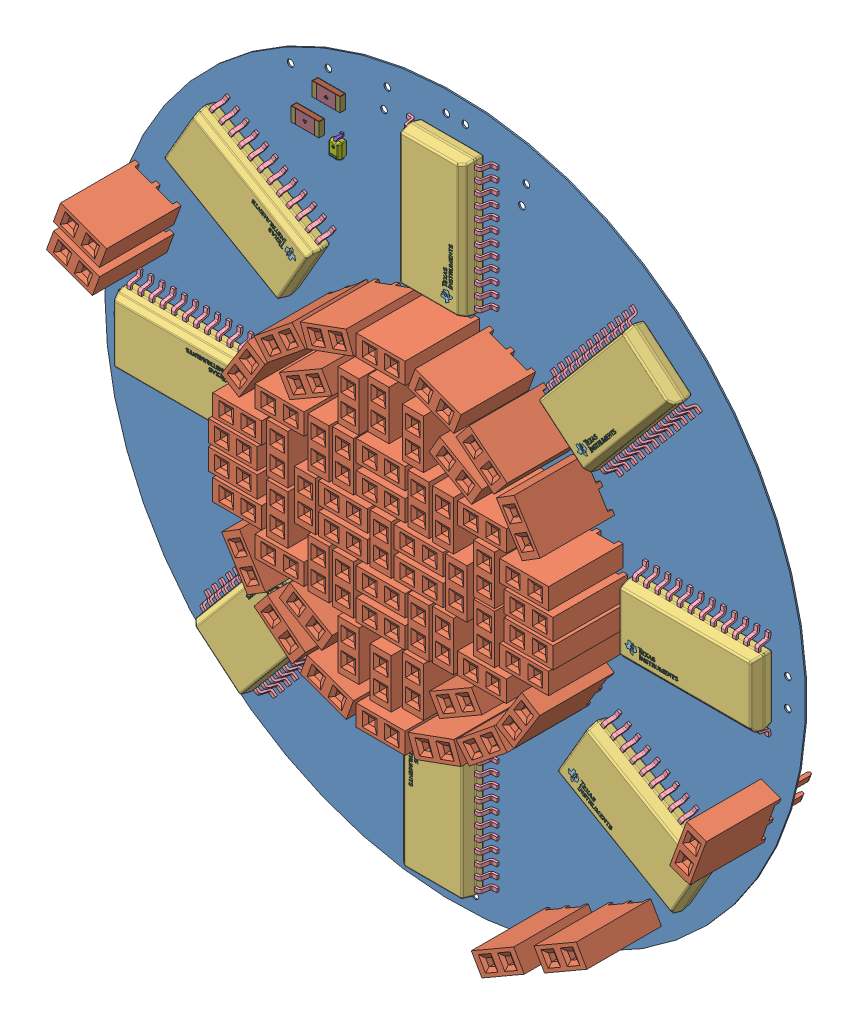
SolidWorks assembly mounting_pcb, configuration Défaut. Lengths in mm.
Overall size (80 80 13.44).
384 component instances, 15 part files, 0 mates.
Components (placement in the parent):
- Board-1: Board [Défaut] at origin size (80 80 0.16)
  - Open CASCADE STEP translator 7.5 1.1.1-1: Open CASCADE STEP translator 7.5 1.1.1 [Défaut] at (0 0 -0.1614) size (80 80 0.16)
- 12-1: 12 [Défaut] at origin size (2.41 5.59 13.44)
  - SSW-102-02-X-S-1: SSW-102-02-X-S [Défaut] at (-11.8109 -2.9211 0) x (1 0 0) z (0 -1 0) size (2.41 13.44 5.59)
- extra3-1: extra3 [Défaut] at origin size (6.05 4.88 13.44)
  - SSW-102-02-X-S-1: SSW-102-02-X-S [Défaut] at (13.3781 -34.6711 0) x (0.5 -0.866025 0) z (-0.866025 -0.5 0) size (2.41 13.44 5.59)
- extra4-1: extra4 [Défaut] at origin size (6.05 4.88 13.44)
  - SSW-102-02-X-S-1: SSW-102-02-X-S [Défaut] at (20.5308 -30.6071 0) x (0.5 -0.866025 0) z (-0.866025 -0.5 0) size (2.41 13.44 5.59)
- extra5-1: extra5 [Défaut] at origin size (4.18 6.08 13.44)
  - SSW-102-02-X-S-1: SSW-102-02-X-S [Défaut] at (35.1053 -13.0305 0) x (-0.939693 0.34202 0) z (0.34202 0.939693 0) size (2.41 13.44 5.59)
- 42-1: 42 [Défaut] at origin size (2.41 5.59 13.44)
  - SSW-102-02-X-S-1: SSW-102-02-X-S [Défaut] at (4.3181 -6.0961 0) x (1 0 0) z (0 -1 0) size (2.41 13.44 5.59)
- extra 1-1: extra 1 [Défaut] at origin size (6.08 4.18 13.44)
  - SSW-102-02-X-S-1: SSW-102-02-X-S [Défaut] at (-35.1287 10.2336 0) x (-0.34202 -0.939693 0) z (-0.939693 0.34202 0) size (2.41 13.44 5.59)
- extra 2-1: extra 2 [Défaut] at origin size (6.08 4.18 13.44)
  - SSW-102-02-X-S-1: SSW-102-02-X-S [Défaut] at (-34.3405 13.3883 0) x (-0.34202 -0.939693 0) z (-0.939693 0.34202 0) size (2.41 13.44 5.59)
- U5-1: U5 [Défaut] at origin size (10.34 15.4 2.65)
  - IC_Texas_Instruments_CD74HC4067M96_eec-1: IC_Texas_Instruments_CD74HC4067M96_eec [Défaut] at (-0.127 28.575 0) x (1 0 0) z (0 0 1) size (10.34 15.4 2.65)
    - BODY-SO-1: BODY-SO [Défaut] at (0 0 1.0825) x (0 1 0) z (1 0 0) size (15.4 2.45 7.5)
    - LEAD-SO-1: LEAD-SO [Défaut] at (4.315 6.985 0.25) x (0 1 0) z (1 0 0) size (0.41 1.43 1.42)
    - LEAD-SO-2: LEAD-SO [Défaut] at (4.315 5.715 0.25) x (0 1 0) z (1 0 0) size (0.41 1.43 1.42)
    - LEAD-SO-3: LEAD-SO [Défaut] at (4.315 4.445 0.25) x (0 1 0) z (1 0 0) size (0.41 1.43 1.42)
    - LEAD-SO-4: LEAD-SO [Défaut] at (4.315 3.175 0.25) x (0 1 0) z (1 0 0) size (0.41 1.43 1.42)
    - LEAD-SO-5: LEAD-SO [Défaut] at (4.315 1.905 0.25) x (0 1 0) z (1 0 0) size (0.41 1.43 1.42)
    - LEAD-SO-6: LEAD-SO [Défaut] at (4.315 0.635 0.25) x (0 1 0) z (1 0 0) size (0.41 1.43 1.42)
    - LEAD-SO-7: LEAD-SO [Défaut] at (4.315 -0.635 0.25) x (0 1 0) z (1 0 0) size (0.41 1.43 1.42)
    - LEAD-SO-8: LEAD-SO [Défaut] at (4.315 -1.905 0.25) x (0 1 0) z (1 0 0) size (0.41 1.43 1.42)
    - LEAD-SO-9: LEAD-SO [Défaut] at (4.315 -3.175 0.25) x (0 1 0) z (1 0 0) size (0.41 1.43 1.42)
    - LEAD-SO-10: LEAD-SO [Défaut] at (4.315 -4.445 0.25) x (0 1 0) z (1 0 0) size (0.41 1.43 1.42)
    - LEAD-SO-11: LEAD-SO [Défaut] at (4.315 -5.715 0.25) x (0 1 0) z (1 0 0) size (0.41 1.43 1.42)
    - LEAD-SO-12: LEAD-SO [Défaut] at (4.315 -6.985 0.25) x (0 1 0) z (1 0 0) size (0.41 1.43 1.42)
    - LEAD-SO-13: LEAD-SO [Défaut] at (-4.315 6.985 0.25) x (0 -1 0) z (-1 0 0) size (0.41 1.43 1.42)
    - LEAD-SO-14: LEAD-SO [Défaut] at (-4.315 5.715 0.25) x (0 -1 0) z (-1 0 0) size (0.41 1.43 1.42)
    - LEAD-SO-15: LEAD-SO [Défaut] at (-4.315 4.445 0.25) x (0 -1 0) z (-1 0 0) size (0.41 1.43 1.42)
    - LEAD-SO-16: LEAD-SO [Défaut] at (-4.315 3.175 0.25) x (0 -1 0) z (-1 0 0) size (0.41 1.43 1.42)
    - LEAD-SO-17: LEAD-SO [Défaut] at (-4.315 1.905 0.25) x (0 -1 0) z (-1 0 0) size (0.41 1.43 1.42)
    - LEAD-SO-18: LEAD-SO [Défaut] at (-4.315 0.635 0.25) x (0 -1 0) z (-1 0 0) size (0.41 1.43 1.42)
    - LEAD-SO-19: LEAD-SO [Défaut] at (-4.315 -0.635 0.25) x (0 -1 0) z (-1 0 0) size (0.41 1.43 1.42)
    - LEAD-SO-20: LEAD-SO [Défaut] at (-4.315 -1.905 0.25) x (0 -1 0) z (-1 0 0) size (0.41 1.43 1.42)
    - LEAD-SO-21: LEAD-SO [Défaut] at (-4.315 -3.175 0.25) x (0 -1 0) z (-1 0 0) size (0.41 1.43 1.42)
    - LEAD-SO-22: LEAD-SO [Défaut] at (-4.315 -4.445 0.25) x (0 -1 0) z (-1 0 0) size (0.41 1.43 1.42)
    - LEAD-SO-23: LEAD-SO [Défaut] at (-4.315 -5.715 0.25) x (0 -1 0) z (-1 0 0) size (0.41 1.43 1.42)
    - LEAD-SO-24: LEAD-SO [Défaut] at (-4.315 -6.985 0.25) x (0 -1 0) z (-1 0 0) size (0.41 1.43 1.42)
    - Texas Logo Yury-1: Texas Logo Yury [Défaut] at (2.174 -7.1221 2.551) x (0 1 0) z (0 0 1) size (1.32 1.29 0.11)
    - Texas Logo Yury - Copy-1: Texas Logo Yury - Copy [Défaut] at (2.0641 -7.1534 2.551) x (0 1 0) z (0 0 1) size (4.61 1.2 0.1)
- Zener1-1: Zener1 [Défaut] at origin size (1.25 2.5 1.12)
  - Diode_ON_Semiconductor_NSR02100HT1G_eec-1: Diode_ON_Semiconductor_NSR02100HT1G_eec [Défaut] at (-12.827 28.829 0) x (0 1 0) z (0 0 1) size (2.5 1.25 1.12)
    - 1-1: 1 [Défaut] at (0 0 0.05) size (1.7 1.25 1.08)
    - 2-1: 2 [Défaut] x (1 0 0) z (0 -1 0) size (2.5 0.9 0.32)
    - ON Semiconductor-1: ON Semiconductor [Défaut] at (0.2865 -0.4575 1.0977) size (0.43 0.38 0.01)
    - bar-1: bar [Défaut] at (0 0 1.1) size (0.22 0.81 0)
- 6-1: 6 [Défaut] at origin size (3.2 1.6 0.65)
  - Res_Vishay_MCA12060D1541BP100_eec-1: Res_Vishay_MCA12060D1541BP100_eec [Défaut] at (-16.5038 29.591 0) x (1 0 0) z (0 0 1) size (3.2 1.6 0.65)
    - body-1: body [Défaut] at (0 0 0.6) x (1 0 0) z (0 0 -1) size (3.1 1.6 0.55)
    - pad-1: pad [Défaut] at (-1.4133 -0.8 0.65) x (1 0 0) z (0 1 0) size (0.5 0.65 1.6)
    - pad-2: pad [Défaut] at (1.4133 0.8 0.65) x (-1 0 0) z (0 -1 0) size (0.5 0.65 1.6)
    - top-1: top [Défaut] at (0 0 0.65) x (1 0 0) z (0 0 -1) size (2.2 1.6 0.05)
    - Vishay-1: Vishay [Défaut] at (0.0405 -0.7888 0.65) size (0.45 0.38 0.01)
    - bottom-1: bottom [Défaut] at (0 0 0.05) x (1 0 0) z (0 0 -1) size (2.2 1.6 0.05)
- res1-1: res1 [Défaut] at origin size (3.2 1.6 0.65)
  - Res_Vishay_MCA12060D1541BP100_eec-1: Res_Vishay_MCA12060D1541BP100_eec [Défaut] at (-14.097 33.274 0) x (-1 0 0) z (0 0 1) size (3.2 1.6 0.65)
    - body-1: body [Défaut] at (0 0 0.6) x (1 0 0) z (0 0 -1) size (3.1 1.6 0.55)
    - pad-1: pad [Défaut] at (-1.4133 -0.8 0.65) x (1 0 0) z (0 1 0) size (0.5 0.65 1.6)
    - pad-2: pad [Défaut] at (1.4133 0.8 0.65) x (-1 0 0) z (0 -1 0) size (0.5 0.65 1.6)
    - top-1: top [Défaut] at (0 0 0.65) x (1 0 0) z (0 0 -1) size (2.2 1.6 0.05)
    - Vishay-1: Vishay [Défaut] at (0.0405 -0.7888 0.65) size (0.45 0.38 0.01)
    - bottom-1: bottom [Défaut] at (0 0 0.05) x (1 0 0) z (0 0 -1) size (2.2 1.6 0.05)
- 60-1: 60 [Défaut] at origin size (5.59 2.41 13.44)
  - SSW-102-02-X-S-1: SSW-102-02-X-S [Défaut] at (16.8911 1.3971 0) x (0 1 0) z (1 0 0) size (2.41 13.44 5.59)
- 58-1: 58 [Défaut] at origin size (5.59 2.41 13.44)
  - SSW-102-02-X-S-1: SSW-102-02-X-S [Défaut] at (16.3831 4.1911 0) x (0 1 0) z (1 0 0) size (2.41 13.44 5.59)
- 56-1: 56 [Défaut] at origin size (5.01 6.02 13.44)
  - SSW-102-02-X-S-1: SSW-102-02-X-S [Défaut] at (15.7101 9.459 0) x (0.848048 0.529919 0) z (0.529919 -0.848048 0) size (2.41 13.44 5.59)
- 49-1: 49 [Défaut] at origin size (5.86 5.39 13.44)
  - SSW-102-02-X-S-1: SSW-102-02-X-S [Défaut] at (11.5281 14.0968 0) x (0.62932 0.777146 0) z (0.777146 -0.62932 0) size (2.41 13.44 5.59)
- 41-1: 41 [Défaut] at origin size (6.08 4.18 13.44)
  - SSW-102-02-X-S-1: SSW-102-02-X-S [Défaut] at (6.1465 17.2187 0) x (0.34202 0.939693 0) z (0.939693 -0.34202 0) size (2.41 13.44 5.59)
- 54-1: 54 [Défaut] at origin size (2.41 5.59 13.44)
  - SSW-102-02-X-S-1: SSW-102-02-X-S [Défaut] at (11.8109 2.9211 0) x (-1 0 0) z (0 1 0) size (2.41 13.44 5.59)
- 52-1: 52 [Défaut] at origin size (5.59 2.41 13.44)
  - SSW-102-02-X-S-1: SSW-102-02-X-S [Défaut] at (11.5571 7.4931 0) x (0 1 0) z (1 0 0) size (2.41 13.44 5.59)
- 45-1: 45 [Défaut] at origin size (6.05 4.88 13.44)
  - SSW-102-02-X-S-1: SSW-102-02-X-S [Défaut] at (8.5523 11.557 0) x (0.5 0.866025 0) z (0.866025 -0.5 0) size (2.41 13.44 5.59)
- 39-1: 39 [Défaut] at origin size (2.41 5.59 13.44)
  - SSW-102-02-X-S-1: SSW-102-02-X-S [Défaut] at (3.6829 12.3191 0) x (-1 0 0) z (0 1 0) size (2.41 13.44 5.59)
- 33-1: 33 [Défaut] at origin size (2.41 5.59 13.44)
  - SSW-102-02-X-S-1: SSW-102-02-X-S [Défaut] at (-0.2541 13.2081 0) x (-1 0 0) z (0 1 0) size (2.41 13.44 5.59)
- 47-1: 47 [Défaut] at origin size (2.41 5.59 13.44)
  - SSW-102-02-X-S-1: SSW-102-02-X-S [Défaut] at (7.1119 5.9691 0) x (-1 0 0) z (0 1 0) size (2.41 13.44 5.59)
- 43-1: 43 [Défaut] at origin size (2.41 5.59 13.44)
  - SSW-102-02-X-S-1: SSW-102-02-X-S [Défaut] at (4.3179 6.0961 0) x (-1 0 0) z (0 1 0) size (2.41 13.44 5.59)
- 31-1: 31 [Défaut] at origin size (5.59 2.41 13.44)
  - SSW-102-02-X-S-1: SSW-102-02-X-S [Défaut] at (0.0001 7.8741 0) x (0 1 0) z (1 0 0) size (2.41 13.44 5.59)
- 37-1: 37 [Défaut] at origin size (5.59 2.41 13.44)
  - SSW-102-02-X-S-1: SSW-102-02-X-S [Défaut] at (4.3181 1.5241 0) x (0 1 0) z (1 0 0) size (2.41 13.44 5.59)
- 30-1: 30 [Défaut] at origin size (5.59 2.41 13.44)
  - SSW-102-02-X-S-1: SSW-102-02-X-S [Défaut] at (0.0001 4.6991 0) x (0 1 0) z (1 0 0) size (2.41 13.44 5.59)
- 35-1: 35 [Défaut] at origin size (2.41 5.59 13.44)
  - SSW-102-02-X-S-1: SSW-102-02-X-S [Défaut] at (-0.0001 0.0001 0) x (-1 0 0) z (0 1 0) size (2.41 13.44 5.59)
- 36-1: 36 [Défaut] at origin size (5.59 2.41 13.44)
  - SSW-102-02-X-S-1: SSW-102-02-X-S [Défaut] at (4.3181 -1.5239 0) x (0 1 0) z (1 0 0) size (2.41 13.44 5.59)
- 29-1: 29 [Défaut] at origin size (5.59 2.41 13.44)
  - SSW-102-02-X-S-1: SSW-102-02-X-S [Défaut] at (0.0001 -4.6989 0) x (0 1 0) z (1 0 0) size (2.41 13.44 5.59)
- 21-1: 21 [Défaut] at origin size (5.59 2.41 13.44)
  - SSW-102-02-X-S-1: SSW-102-02-X-S [Défaut] at (-4.3181 -1.5241 0) x (0 -1 0) z (-1 0 0) size (2.41 13.44 5.59)
- 22-1: 22 [Défaut] at origin size (5.59 2.41 13.44)
  - SSW-102-02-X-S-1: SSW-102-02-X-S [Défaut] at (-4.3181 1.5239 0) x (0 -1 0) z (-1 0 0) size (2.41 13.44 5.59)
- 48-1: 48 [Défaut] at origin size (2.41 5.59 13.44)
  - SSW-102-02-X-S-1: SSW-102-02-X-S [Défaut] at (8.6359 0.0001 0) x (-1 0 0) z (0 1 0) size (2.41 13.44 5.59)
- 46-1: 46 [Défaut] at origin size (2.41 5.59 13.44)
  - SSW-102-02-X-S-1: SSW-102-02-X-S [Défaut] at (7.1121 -5.9691 0) x (1 0 0) z (0 -1 0) size (2.41 13.44 5.59)
- 16-1: 16 [Défaut] at origin size (2.41 5.59 13.44)
  - SSW-102-02-X-S-1: SSW-102-02-X-S [Défaut] at (-8.6359 -0.0001 0) x (1 0 0) z (0 -1 0) size (2.41 13.44 5.59)
- 28-1: 28 [Défaut] at origin size (5.59 2.41 13.44)
  - SSW-102-02-X-S-1: SSW-102-02-X-S [Défaut] at (0.0001 -7.8739 0) x (0 1 0) z (1 0 0) size (2.41 13.44 5.59)
- 23-1: 23 [Défaut] at origin size (2.41 5.59 13.44)
  - SSW-102-02-X-S-1: SSW-102-02-X-S [Défaut] at (-4.3179 -6.0961 0) x (1 0 0) z (0 -1 0) size (2.41 13.44 5.59)
- 19-1: 19 [Défaut] at origin size (2.41 5.59 13.44)
  - SSW-102-02-X-S-1: SSW-102-02-X-S [Défaut] at (-7.1119 -5.9691 0) x (1 0 0) z (0 -1 0) size (2.41 13.44 5.59)
- 20-1: 20 [Défaut] at origin size (2.41 5.59 13.44)
  - SSW-102-02-X-S-1: SSW-102-02-X-S [Défaut] at (-7.1121 5.9691 0) x (-1 0 0) z (0 1 0) size (2.41 13.44 5.59)
- 24-1: 24 [Défaut] at origin size (2.41 5.59 13.44)
  - SSW-102-02-X-S-1: SSW-102-02-X-S [Défaut] at (-4.3181 6.0961 0) x (-1 0 0) z (0 1 0) size (2.41 13.44 5.59)
- 53-1: 53 [Défaut] at origin size (2.41 5.59 13.44)
  - SSW-102-02-X-S-1: SSW-102-02-X-S [Défaut] at (11.8111 -2.9211 0) x (1 0 0) z (0 -1 0) size (2.41 13.44 5.59)
- 51-1: 51 [Défaut] at origin size (5.59 2.41 13.44)
  - SSW-102-02-X-S-1: SSW-102-02-X-S [Défaut] at (11.5571 -7.3659 0) x (0 1 0) z (1 0 0) size (2.41 13.44 5.59)
- 44-1: 44 [Défaut] at origin size (6.05 4.88 13.44)
  - SSW-102-02-X-S-1: SSW-102-02-X-S [Défaut] at (8.5519 -11.4299 0) x (-0.5 0.866025 0) z (0.866025 0.5 0) size (2.41 13.44 5.59)
- 38-1: 38 [Défaut] at origin size (2.41 5.59 13.44)
  - SSW-102-02-X-S-1: SSW-102-02-X-S [Défaut] at (3.6831 -12.1921 0) x (1 0 0) z (0 -1 0) size (2.41 13.44 5.59)
- 34-1: 34 [Défaut] at origin size (2.41 5.59 13.44)
  - SSW-102-02-X-S-1: SSW-102-02-X-S [Défaut] at (0.0001 -13.2081 0) x (1 0 0) z (0 -1 0) size (2.41 13.44 5.59)
- 25-1: 25 [Défaut] at origin size (2.41 5.59 13.44)
  - SSW-102-02-X-S-1: SSW-102-02-X-S [Défaut] at (-3.6829 -12.3191 0) x (1 0 0) z (0 -1 0) size (2.41 13.44 5.59)
- 14-1: 14 [Défaut] at origin size (6.05 4.88 13.44)
  - SSW-102-02-X-S-1: SSW-102-02-X-S [Défaut] at (-8.5523 -11.43 0) x (-0.5 -0.866025 0) z (-0.866025 0.5 0) size (2.41 13.44 5.59)
- 10-1: 10 [Défaut] at origin size (5.59 2.41 13.44)
  - SSW-102-02-X-S-1: SSW-102-02-X-S [Défaut] at (-11.5571 -7.3661 0) x (0 -1 0) z (-1 0 0) size (2.41 13.44 5.59)
- 13-1: 13 [Défaut] at origin size (2.41 5.59 13.44)
  - SSW-102-02-X-S-1: SSW-102-02-X-S [Défaut] at (-11.8111 3.0481 0) x (-1 0 0) z (0 1 0) size (2.41 13.44 5.59)
- 11-1: 11 [Défaut] at origin size (5.59 2.41 13.44)
  - SSW-102-02-X-S-1: SSW-102-02-X-S [Défaut] at (-11.5571 7.4929 0) x (0 -1 0) z (-1 0 0) size (2.41 13.44 5.59)
- 15-1: 15 [Défaut] at origin size (6.05 4.88 13.44)
  - SSW-102-02-X-S-1: SSW-102-02-X-S [Défaut] at (-8.5519 11.5569 0) x (0.5 -0.866025 0) z (-0.866025 -0.5 0) size (2.41 13.44 5.59)
- 26-1: 26 [Défaut] at origin size (2.41 5.59 13.44)
  - SSW-102-02-X-S-1: SSW-102-02-X-S [Défaut] at (-3.6831 12.3191 0) x (-1 0 0) z (0 1 0) size (2.41 13.44 5.59)
- 32-1: 32 [Défaut] at origin size (5.59 2.41 13.44)
  - SSW-102-02-X-S-1: SSW-102-02-X-S [Défaut] at (0.0001 18.2881 0) x (0 1 0) z (1 0 0) size (2.41 13.44 5.59)
- 59-1: 59 [Défaut] at origin size (5.59 2.41 13.44)
  - SSW-102-02-X-S-1: SSW-102-02-X-S [Défaut] at (16.8911 -1.3969 0) x (0 1 0) z (1 0 0) size (2.41 13.44 5.59)
- 57-1: 57 [Défaut] at origin size (5.59 2.41 13.44)
  - SSW-102-02-X-S-1: SSW-102-02-X-S [Défaut] at (16.3831 -4.1909 0) x (0 1 0) z (1 0 0) size (2.41 13.44 5.59)
- 55-1: 55 [Défaut] at origin size (5.01 6.02 13.44)
  - SSW-102-02-X-S-1: SSW-102-02-X-S [Défaut] at (15.659 -9.5909 0) x (-0.848048 0.529919 0) z (0.529919 0.848048 0) size (2.41 13.44 5.59)
- 50-1: 50 [Défaut] at origin size (5.86 5.39 13.44)
  - SSW-102-02-X-S-1: SSW-102-02-X-S [Défaut] at (11.528 -14.1866 0) x (-0.62932 0.777146 0) z (0.777146 0.62932 0) size (2.41 13.44 5.59)
- 40-1: 40 [Défaut] at origin size (6.08 4.18 13.44)
  - SSW-102-02-X-S-1: SSW-102-02-X-S [Défaut] at (6.1465 -17.2185 0) x (-0.34202 0.939693 0) z (0.939693 0.34202 0) size (2.41 13.44 5.59)
- 27-1: 27 [Défaut] at origin size (5.59 2.41 13.44)
  - SSW-102-02-X-S-1: SSW-102-02-X-S [Défaut] at (-0.0001 -18.2881 0) x (0 -1 0) z (-1 0 0) size (2.41 13.44 5.59)
- 17-1: 17 [Défaut] at origin size (6.08 4.18 13.44)
  - SSW-102-02-X-S-1: SSW-102-02-X-S [Défaut] at (-6.1465 -17.2187 0) x (-0.34202 -0.939693 0) z (-0.939693 0.34202 0) size (2.41 13.44 5.59)
- 8-1: 8 [Défaut] at origin size (5.86 5.39 13.44)
  - SSW-102-02-X-S-1: SSW-102-02-X-S [Défaut] at (-11.5281 -14.1868 0) x (-0.62932 -0.777146 0) z (-0.777146 0.62932 0) size (2.41 13.44 5.59)
- 7-1: 7 [Défaut] at origin size (5.01 6.02 13.44)
  - SSW-102-02-X-S-1: SSW-102-02-X-S [Défaut] at (-15.6591 -9.591 0) x (-0.848048 -0.529919 0) z (-0.529919 0.848048 0) size (2.41 13.44 5.59)
- 3-1: 3 [Défaut] at origin size (5.59 2.41 13.44)
  - SSW-102-02-X-S-1: SSW-102-02-X-S [Défaut] at (-16.3831 -4.1911 0) x (0 -1 0) z (-1 0 0) size (2.41 13.44 5.59)
- 1-1: 1 [Défaut] at origin size (5.59 2.41 13.44)
  - SSW-102-02-X-S-1: SSW-102-02-X-S [Défaut] at (-16.8911 -1.3971 0) x (0 -1 0) z (-1 0 0) size (2.41 13.44 5.59)
- 2-1: 2 [Défaut] at origin size (5.59 2.41 13.44)
  - SSW-102-02-X-S-1: SSW-102-02-X-S [Défaut] at (-16.8911 1.3969 0) x (0 -1 0) z (-1 0 0) size (2.41 13.44 5.59)
- 4-1: 4 [Défaut] at origin size (5.59 2.41 13.44)
  - SSW-102-02-X-S-1: SSW-102-02-X-S [Défaut] at (-16.3831 4.1909 0) x (0 -1 0) z (-1 0 0) size (2.41 13.44 5.59)
- 5-1: 5 [Défaut] at origin size (5.01 6.02 13.44)
  - SSW-102-02-X-S-1: SSW-102-02-X-S [Défaut] at (-15.71 9.4589 0) x (0.848048 -0.529919 0) z (-0.529919 -0.848048 0) size (2.41 13.44 5.59)
- 9-1: 9 [Défaut] at origin size (5.86 5.39 13.44)
  - SSW-102-02-X-S-1: SSW-102-02-X-S [Défaut] at (-11.528 14.1866 0) x (0.62932 -0.777146 0) z (-0.777146 -0.62932 0) size (2.41 13.44 5.59)
- 18-1: 18 [Défaut] at origin size (6.08 4.18 13.44)
  - SSW-102-02-X-S-1: SSW-102-02-X-S [Défaut] at (-6.1465 17.2185 0) x (0.34202 -0.939693 0) z (-0.939693 -0.34202 0) size (2.41 13.44 5.59)
- U8-1: U8 [Défaut] at origin size (15.4 10.34 2.65)
  - IC_Texas_Instruments_CD74HC4067M96_eec-1: IC_Texas_Instruments_CD74HC4067M96_eec [Défaut] at (28.875 0 0) x (0 -1 0) z (0 0 1) size (10.34 15.4 2.65)
    - BODY-SO-1: BODY-SO [Défaut] at (0 0 1.0825) x (0 1 0) z (1 0 0) size (15.4 2.45 7.5)
    - LEAD-SO-1: LEAD-SO [Défaut] at (4.315 6.985 0.25) x (0 1 0) z (1 0 0) size (0.41 1.43 1.42)
    - LEAD-SO-2: LEAD-SO [Défaut] at (4.315 5.715 0.25) x (0 1 0) z (1 0 0) size (0.41 1.43 1.42)
    - LEAD-SO-3: LEAD-SO [Défaut] at (4.315 4.445 0.25) x (0 1 0) z (1 0 0) size (0.41 1.43 1.42)
    - LEAD-SO-4: LEAD-SO [Défaut] at (4.315 3.175 0.25) x (0 1 0) z (1 0 0) size (0.41 1.43 1.42)
    - LEAD-SO-5: LEAD-SO [Défaut] at (4.315 1.905 0.25) x (0 1 0) z (1 0 0) size (0.41 1.43 1.42)
    - LEAD-SO-6: LEAD-SO [Défaut] at (4.315 0.635 0.25) x (0 1 0) z (1 0 0) size (0.41 1.43 1.42)
    - LEAD-SO-7: LEAD-SO [Défaut] at (4.315 -0.635 0.25) x (0 1 0) z (1 0 0) size (0.41 1.43 1.42)
    - LEAD-SO-8: LEAD-SO [Défaut] at (4.315 -1.905 0.25) x (0 1 0) z (1 0 0) size (0.41 1.43 1.42)
    - LEAD-SO-9: LEAD-SO [Défaut] at (4.315 -3.175 0.25) x (0 1 0) z (1 0 0) size (0.41 1.43 1.42)
    - LEAD-SO-10: LEAD-SO [Défaut] at (4.315 -4.445 0.25) x (0 1 0) z (1 0 0) size (0.41 1.43 1.42)
    - LEAD-SO-11: LEAD-SO [Défaut] at (4.315 -5.715 0.25) x (0 1 0) z (1 0 0) size (0.41 1.43 1.42)
    - LEAD-SO-12: LEAD-SO [Défaut] at (4.315 -6.985 0.25) x (0 1 0) z (1 0 0) size (0.41 1.43 1.42)
    - LEAD-SO-13: LEAD-SO [Défaut] at (-4.315 6.985 0.25) x (0 -1 0) z (-1 0 0) size (0.41 1.43 1.42)
    - LEAD-SO-14: LEAD-SO [Défaut] at (-4.315 5.715 0.25) x (0 -1 0) z (-1 0 0) size (0.41 1.43 1.42)
    - LEAD-SO-15: LEAD-SO [Défaut] at (-4.315 4.445 0.25) x (0 -1 0) z (-1 0 0) size (0.41 1.43 1.42)
    - LEAD-SO-16: LEAD-SO [Défaut] at (-4.315 3.175 0.25) x (0 -1 0) z (-1 0 0) size (0.41 1.43 1.42)
    - LEAD-SO-17: LEAD-SO [Défaut] at (-4.315 1.905 0.25) x (0 -1 0) z (-1 0 0) size (0.41 1.43 1.42)
    - LEAD-SO-18: LEAD-SO [Défaut] at (-4.315 0.635 0.25) x (0 -1 0) z (-1 0 0) size (0.41 1.43 1.42)
    - LEAD-SO-19: LEAD-SO [Défaut] at (-4.315 -0.635 0.25) x (0 -1 0) z (-1 0 0) size (0.41 1.43 1.42)
    - LEAD-SO-20: LEAD-SO [Défaut] at (-4.315 -1.905 0.25) x (0 -1 0) z (-1 0 0) size (0.41 1.43 1.42)
    - LEAD-SO-21: LEAD-SO [Défaut] at (-4.315 -3.175 0.25) x (0 -1 0) z (-1 0 0) size (0.41 1.43 1.42)
    - LEAD-SO-22: LEAD-SO [Défaut] at (-4.315 -4.445 0.25) x (0 -1 0) z (-1 0 0) size (0.41 1.43 1.42)
    - LEAD-SO-23: LEAD-SO [Défaut] at (-4.315 -5.715 0.25) x (0 -1 0) z (-1 0 0) size (0.41 1.43 1.42)
    - LEAD-SO-24: LEAD-SO [Défaut] at (-4.315 -6.985 0.25) x (0 -1 0) z (-1 0 0) size (0.41 1.43 1.42)
    - Texas Logo Yury-1: Texas Logo Yury [Défaut] at (2.174 -7.1221 2.551) x (0 1 0) z (0 0 1) size (1.32 1.29 0.11)
    - Texas Logo Yury - Copy-1: Texas Logo Yury - Copy [Défaut] at (2.0641 -7.1534 2.551) x (0 1 0) z (0 0 1) size (4.61 1.2 0.1)
- U4-1: U4 [Défaut] at origin size (10.34 15.4 2.65)
  - IC_Texas_Instruments_CD74HC4067M96_eec-1: IC_Texas_Instruments_CD74HC4067M96_eec [Défaut] at (-0.127 -28.875 0) x (-1 0 0) z (0 0 1) size (10.34 15.4 2.65)
    - BODY-SO-1: BODY-SO [Défaut] at (0 0 1.0825) x (0 1 0) z (1 0 0) size (15.4 2.45 7.5)
    - LEAD-SO-1: LEAD-SO [Défaut] at (4.315 6.985 0.25) x (0 1 0) z (1 0 0) size (0.41 1.43 1.42)
    - LEAD-SO-2: LEAD-SO [Défaut] at (4.315 5.715 0.25) x (0 1 0) z (1 0 0) size (0.41 1.43 1.42)
    - LEAD-SO-3: LEAD-SO [Défaut] at (4.315 4.445 0.25) x (0 1 0) z (1 0 0) size (0.41 1.43 1.42)
    - LEAD-SO-4: LEAD-SO [Défaut] at (4.315 3.175 0.25) x (0 1 0) z (1 0 0) size (0.41 1.43 1.42)
    - LEAD-SO-5: LEAD-SO [Défaut] at (4.315 1.905 0.25) x (0 1 0) z (1 0 0) size (0.41 1.43 1.42)
    - LEAD-SO-6: LEAD-SO [Défaut] at (4.315 0.635 0.25) x (0 1 0) z (1 0 0) size (0.41 1.43 1.42)
    - LEAD-SO-7: LEAD-SO [Défaut] at (4.315 -0.635 0.25) x (0 1 0) z (1 0 0) size (0.41 1.43 1.42)
    - LEAD-SO-8: LEAD-SO [Défaut] at (4.315 -1.905 0.25) x (0 1 0) z (1 0 0) size (0.41 1.43 1.42)
    - LEAD-SO-9: LEAD-SO [Défaut] at (4.315 -3.175 0.25) x (0 1 0) z (1 0 0) size (0.41 1.43 1.42)
    - LEAD-SO-10: LEAD-SO [Défaut] at (4.315 -4.445 0.25) x (0 1 0) z (1 0 0) size (0.41 1.43 1.42)
    - LEAD-SO-11: LEAD-SO [Défaut] at (4.315 -5.715 0.25) x (0 1 0) z (1 0 0) size (0.41 1.43 1.42)
    - LEAD-SO-12: LEAD-SO [Défaut] at (4.315 -6.985 0.25) x (0 1 0) z (1 0 0) size (0.41 1.43 1.42)
    - LEAD-SO-13: LEAD-SO [Défaut] at (-4.315 6.985 0.25) x (0 -1 0) z (-1 0 0) size (0.41 1.43 1.42)
    - LEAD-SO-14: LEAD-SO [Défaut] at (-4.315 5.715 0.25) x (0 -1 0) z (-1 0 0) size (0.41 1.43 1.42)
    - LEAD-SO-15: LEAD-SO [Défaut] at (-4.315 4.445 0.25) x (0 -1 0) z (-1 0 0) size (0.41 1.43 1.42)
    - LEAD-SO-16: LEAD-SO [Défaut] at (-4.315 3.175 0.25) x (0 -1 0) z (-1 0 0) size (0.41 1.43 1.42)
    - LEAD-SO-17: LEAD-SO [Défaut] at (-4.315 1.905 0.25) x (0 -1 0) z (-1 0 0) size (0.41 1.43 1.42)
    - LEAD-SO-18: LEAD-SO [Défaut] at (-4.315 0.635 0.25) x (0 -1 0) z (-1 0 0) size (0.41 1.43 1.42)
    - LEAD-SO-19: LEAD-SO [Défaut] at (-4.315 -0.635 0.25) x (0 -1 0) z (-1 0 0) size (0.41 1.43 1.42)
    - LEAD-SO-20: LEAD-SO [Défaut] at (-4.315 -1.905 0.25) x (0 -1 0) z (-1 0 0) size (0.41 1.43 1.42)
    - LEAD-SO-21: LEAD-SO [Défaut] at (-4.315 -3.175 0.25) x (0 -1 0) z (-1 0 0) size (0.41 1.43 1.42)
    - LEAD-SO-22: LEAD-SO [Défaut] at (-4.315 -4.445 0.25) x (0 -1 0) z (-1 0 0) size (0.41 1.43 1.42)
    - LEAD-SO-23: LEAD-SO [Défaut] at (-4.315 -5.715 0.25) x (0 -1 0) z (-1 0 0) size (0.41 1.43 1.42)
    - LEAD-SO-24: LEAD-SO [Défaut] at (-4.315 -6.985 0.25) x (0 -1 0) z (-1 0 0) size (0.41 1.43 1.42)
    - Texas Logo Yury-1: Texas Logo Yury [Défaut] at (2.174 -7.1221 2.551) x (0 1 0) z (0 0 1) size (1.32 1.29 0.11)
    - Texas Logo Yury - Copy-1: Texas Logo Yury - Copy [Défaut] at (2.0641 -7.1534 2.551) x (0 1 0) z (0 0 1) size (4.61 1.2 0.1)
- U6-1: U6 [Défaut] at origin size (17.82 18.44 2.65)
  - IC_Texas_Instruments_CD74HC4067M96_eec-1: IC_Texas_Instruments_CD74HC4067M96_eec [Défaut] at (19.685 20.828 0) x (0.766044 -0.642788 0) z (0 0 1) size (10.34 15.4 2.65)
    - BODY-SO-1: BODY-SO [Défaut] at (0 0 1.0825) x (0 1 0) z (1 0 0) size (15.4 2.45 7.5)
    - LEAD-SO-1: LEAD-SO [Défaut] at (4.315 6.985 0.25) x (0 1 0) z (1 0 0) size (0.41 1.43 1.42)
    - LEAD-SO-2: LEAD-SO [Défaut] at (4.315 5.715 0.25) x (0 1 0) z (1 0 0) size (0.41 1.43 1.42)
    - LEAD-SO-3: LEAD-SO [Défaut] at (4.315 4.445 0.25) x (0 1 0) z (1 0 0) size (0.41 1.43 1.42)
    - LEAD-SO-4: LEAD-SO [Défaut] at (4.315 3.175 0.25) x (0 1 0) z (1 0 0) size (0.41 1.43 1.42)
    - LEAD-SO-5: LEAD-SO [Défaut] at (4.315 1.905 0.25) x (0 1 0) z (1 0 0) size (0.41 1.43 1.42)
    - LEAD-SO-6: LEAD-SO [Défaut] at (4.315 0.635 0.25) x (0 1 0) z (1 0 0) size (0.41 1.43 1.42)
    - LEAD-SO-7: LEAD-SO [Défaut] at (4.315 -0.635 0.25) x (0 1 0) z (1 0 0) size (0.41 1.43 1.42)
    - LEAD-SO-8: LEAD-SO [Défaut] at (4.315 -1.905 0.25) x (0 1 0) z (1 0 0) size (0.41 1.43 1.42)
    - LEAD-SO-9: LEAD-SO [Défaut] at (4.315 -3.175 0.25) x (0 1 0) z (1 0 0) size (0.41 1.43 1.42)
    - LEAD-SO-10: LEAD-SO [Défaut] at (4.315 -4.445 0.25) x (0 1 0) z (1 0 0) size (0.41 1.43 1.42)
    - LEAD-SO-11: LEAD-SO [Défaut] at (4.315 -5.715 0.25) x (0 1 0) z (1 0 0) size (0.41 1.43 1.42)
    - LEAD-SO-12: LEAD-SO [Défaut] at (4.315 -6.985 0.25) x (0 1 0) z (1 0 0) size (0.41 1.43 1.42)
    - LEAD-SO-13: LEAD-SO [Défaut] at (-4.315 6.985 0.25) x (0 -1 0) z (-1 0 0) size (0.41 1.43 1.42)
    - LEAD-SO-14: LEAD-SO [Défaut] at (-4.315 5.715 0.25) x (0 -1 0) z (-1 0 0) size (0.41 1.43 1.42)
    - LEAD-SO-15: LEAD-SO [Défaut] at (-4.315 4.445 0.25) x (0 -1 0) z (-1 0 0) size (0.41 1.43 1.42)
    - LEAD-SO-16: LEAD-SO [Défaut] at (-4.315 3.175 0.25) x (0 -1 0) z (-1 0 0) size (0.41 1.43 1.42)
    - LEAD-SO-17: LEAD-SO [Défaut] at (-4.315 1.905 0.25) x (0 -1 0) z (-1 0 0) size (0.41 1.43 1.42)
    - LEAD-SO-18: LEAD-SO [Défaut] at (-4.315 0.635 0.25) x (0 -1 0) z (-1 0 0) size (0.41 1.43 1.42)
    - LEAD-SO-19: LEAD-SO [Défaut] at (-4.315 -0.635 0.25) x (0 -1 0) z (-1 0 0) size (0.41 1.43 1.42)
    - LEAD-SO-20: LEAD-SO [Défaut] at (-4.315 -1.905 0.25) x (0 -1 0) z (-1 0 0) size (0.41 1.43 1.42)
    - LEAD-SO-21: LEAD-SO [Défaut] at (-4.315 -3.175 0.25) x (0 -1 0) z (-1 0 0) size (0.41 1.43 1.42)
    - LEAD-SO-22: LEAD-SO [Défaut] at (-4.315 -4.445 0.25) x (0 -1 0) z (-1 0 0) size (0.41 1.43 1.42)
    - LEAD-SO-23: LEAD-SO [Défaut] at (-4.315 -5.715 0.25) x (0 -1 0) z (-1 0 0) size (0.41 1.43 1.42)
    - LEAD-SO-24: LEAD-SO [Défaut] at (-4.315 -6.985 0.25) x (0 -1 0) z (-1 0 0) size (0.41 1.43 1.42)
    - Texas Logo Yury-1: Texas Logo Yury [Défaut] at (2.174 -7.1221 2.551) x (0 1 0) z (0 0 1) size (1.32 1.29 0.11)
    - Texas Logo Yury - Copy-1: Texas Logo Yury - Copy [Défaut] at (2.0641 -7.1534 2.551) x (0 1 0) z (0 0 1) size (4.61 1.2 0.1)
- U7-1: U7 [Défaut] at origin size (18.51 16.65 2.65)
  - IC_Texas_Instruments_CD74HC4067M96_eec-1: IC_Texas_Instruments_CD74HC4067M96_eec [Défaut] at (22.368 -19.247 0) x (-0.5 -0.866025 0) z (0 0 1) size (10.34 15.4 2.65)
    - BODY-SO-1: BODY-SO [Défaut] at (0 0 1.0825) x (0 1 0) z (1 0 0) size (15.4 2.45 7.5)
    - LEAD-SO-1: LEAD-SO [Défaut] at (4.315 6.985 0.25) x (0 1 0) z (1 0 0) size (0.41 1.43 1.42)
    - LEAD-SO-2: LEAD-SO [Défaut] at (4.315 5.715 0.25) x (0 1 0) z (1 0 0) size (0.41 1.43 1.42)
    - LEAD-SO-3: LEAD-SO [Défaut] at (4.315 4.445 0.25) x (0 1 0) z (1 0 0) size (0.41 1.43 1.42)
    - LEAD-SO-4: LEAD-SO [Défaut] at (4.315 3.175 0.25) x (0 1 0) z (1 0 0) size (0.41 1.43 1.42)
    - LEAD-SO-5: LEAD-SO [Défaut] at (4.315 1.905 0.25) x (0 1 0) z (1 0 0) size (0.41 1.43 1.42)
    - LEAD-SO-6: LEAD-SO [Défaut] at (4.315 0.635 0.25) x (0 1 0) z (1 0 0) size (0.41 1.43 1.42)
    - LEAD-SO-7: LEAD-SO [Défaut] at (4.315 -0.635 0.25) x (0 1 0) z (1 0 0) size (0.41 1.43 1.42)
    - LEAD-SO-8: LEAD-SO [Défaut] at (4.315 -1.905 0.25) x (0 1 0) z (1 0 0) size (0.41 1.43 1.42)
    - LEAD-SO-9: LEAD-SO [Défaut] at (4.315 -3.175 0.25) x (0 1 0) z (1 0 0) size (0.41 1.43 1.42)
    - LEAD-SO-10: LEAD-SO [Défaut] at (4.315 -4.445 0.25) x (0 1 0) z (1 0 0) size (0.41 1.43 1.42)
    - LEAD-SO-11: LEAD-SO [Défaut] at (4.315 -5.715 0.25) x (0 1 0) z (1 0 0) size (0.41 1.43 1.42)
    - LEAD-SO-12: LEAD-SO [Défaut] at (4.315 -6.985 0.25) x (0 1 0) z (1 0 0) size (0.41 1.43 1.42)
    - LEAD-SO-13: LEAD-SO [Défaut] at (-4.315 6.985 0.25) x (0 -1 0) z (-1 0 0) size (0.41 1.43 1.42)
    - LEAD-SO-14: LEAD-SO [Défaut] at (-4.315 5.715 0.25) x (0 -1 0) z (-1 0 0) size (0.41 1.43 1.42)
    - LEAD-SO-15: LEAD-SO [Défaut] at (-4.315 4.445 0.25) x (0 -1 0) z (-1 0 0) size (0.41 1.43 1.42)
    - LEAD-SO-16: LEAD-SO [Défaut] at (-4.315 3.175 0.25) x (0 -1 0) z (-1 0 0) size (0.41 1.43 1.42)
    - LEAD-SO-17: LEAD-SO [Défaut] at (-4.315 1.905 0.25) x (0 -1 0) z (-1 0 0) size (0.41 1.43 1.42)
    - LEAD-SO-18: LEAD-SO [Défaut] at (-4.315 0.635 0.25) x (0 -1 0) z (-1 0 0) size (0.41 1.43 1.42)
    - LEAD-SO-19: LEAD-SO [Défaut] at (-4.315 -0.635 0.25) x (0 -1 0) z (-1 0 0) size (0.41 1.43 1.42)
    - LEAD-SO-20: LEAD-SO [Défaut] at (-4.315 -1.905 0.25) x (0 -1 0) z (-1 0 0) size (0.41 1.43 1.42)
    - LEAD-SO-21: LEAD-SO [Défaut] at (-4.315 -3.175 0.25) x (0 -1 0) z (-1 0 0) size (0.41 1.43 1.42)
    - LEAD-SO-22: LEAD-SO [Défaut] at (-4.315 -4.445 0.25) x (0 -1 0) z (-1 0 0) size (0.41 1.43 1.42)
    - LEAD-SO-23: LEAD-SO [Défaut] at (-4.315 -5.715 0.25) x (0 -1 0) z (-1 0 0) size (0.41 1.43 1.42)
    - LEAD-SO-24: LEAD-SO [Défaut] at (-4.315 -6.985 0.25) x (0 -1 0) z (-1 0 0) size (0.41 1.43 1.42)
    - Texas Logo Yury-1: Texas Logo Yury [Défaut] at (2.174 -7.1221 2.551) x (0 1 0) z (0 0 1) size (1.32 1.29 0.11)
    - Texas Logo Yury - Copy-1: Texas Logo Yury - Copy [Défaut] at (2.0641 -7.1534 2.551) x (0 1 0) z (0 0 1) size (4.61 1.2 0.1)
- U1-1: U1 [Défaut] at origin size (15.4 10.34 2.65)
  - IC_Texas_Instruments_CD74HC4067M96_eec-1: IC_Texas_Instruments_CD74HC4067M96_eec [Défaut] at (-28.875 0 0) x (0 1 0) z (0 0 1) size (10.34 15.4 2.65)
    - BODY-SO-1: BODY-SO [Défaut] at (0 0 1.0825) x (0 1 0) z (1 0 0) size (15.4 2.45 7.5)
    - LEAD-SO-1: LEAD-SO [Défaut] at (4.315 6.985 0.25) x (0 1 0) z (1 0 0) size (0.41 1.43 1.42)
    - LEAD-SO-2: LEAD-SO [Défaut] at (4.315 5.715 0.25) x (0 1 0) z (1 0 0) size (0.41 1.43 1.42)
    - LEAD-SO-3: LEAD-SO [Défaut] at (4.315 4.445 0.25) x (0 1 0) z (1 0 0) size (0.41 1.43 1.42)
    - LEAD-SO-4: LEAD-SO [Défaut] at (4.315 3.175 0.25) x (0 1 0) z (1 0 0) size (0.41 1.43 1.42)
    - LEAD-SO-5: LEAD-SO [Défaut] at (4.315 1.905 0.25) x (0 1 0) z (1 0 0) size (0.41 1.43 1.42)
    - LEAD-SO-6: LEAD-SO [Défaut] at (4.315 0.635 0.25) x (0 1 0) z (1 0 0) size (0.41 1.43 1.42)
    - LEAD-SO-7: LEAD-SO [Défaut] at (4.315 -0.635 0.25) x (0 1 0) z (1 0 0) size (0.41 1.43 1.42)
    - LEAD-SO-8: LEAD-SO [Défaut] at (4.315 -1.905 0.25) x (0 1 0) z (1 0 0) size (0.41 1.43 1.42)
    - LEAD-SO-9: LEAD-SO [Défaut] at (4.315 -3.175 0.25) x (0 1 0) z (1 0 0) size (0.41 1.43 1.42)
    - LEAD-SO-10: LEAD-SO [Défaut] at (4.315 -4.445 0.25) x (0 1 0) z (1 0 0) size (0.41 1.43 1.42)
    - LEAD-SO-11: LEAD-SO [Défaut] at (4.315 -5.715 0.25) x (0 1 0) z (1 0 0) size (0.41 1.43 1.42)
    - LEAD-SO-12: LEAD-SO [Défaut] at (4.315 -6.985 0.25) x (0 1 0) z (1 0 0) size (0.41 1.43 1.42)
    - LEAD-SO-13: LEAD-SO [Défaut] at (-4.315 6.985 0.25) x (0 -1 0) z (-1 0 0) size (0.41 1.43 1.42)
    - LEAD-SO-14: LEAD-SO [Défaut] at (-4.315 5.715 0.25) x (0 -1 0) z (-1 0 0) size (0.41 1.43 1.42)
    - LEAD-SO-15: LEAD-SO [Défaut] at (-4.315 4.445 0.25) x (0 -1 0) z (-1 0 0) size (0.41 1.43 1.42)
    - LEAD-SO-16: LEAD-SO [Défaut] at (-4.315 3.175 0.25) x (0 -1 0) z (-1 0 0) size (0.41 1.43 1.42)
    - LEAD-SO-17: LEAD-SO [Défaut] at (-4.315 1.905 0.25) x (0 -1 0) z (-1 0 0) size (0.41 1.43 1.42)
    - LEAD-SO-18: LEAD-SO [Défaut] at (-4.315 0.635 0.25) x (0 -1 0) z (-1 0 0) size (0.41 1.43 1.42)
    - LEAD-SO-19: LEAD-SO [Défaut] at (-4.315 -0.635 0.25) x (0 -1 0) z (-1 0 0) size (0.41 1.43 1.42)
    - LEAD-SO-20: LEAD-SO [Défaut] at (-4.315 -1.905 0.25) x (0 -1 0) z (-1 0 0) size (0.41 1.43 1.42)
    - LEAD-SO-21: LEAD-SO [Défaut] at (-4.315 -3.175 0.25) x (0 -1 0) z (-1 0 0) size (0.41 1.43 1.42)
    - LEAD-SO-22: LEAD-SO [Défaut] at (-4.315 -4.445 0.25) x (0 -1 0) z (-1 0 0) size (0.41 1.43 1.42)
    - LEAD-SO-23: LEAD-SO [Défaut] at (-4.315 -5.715 0.25) x (0 -1 0) z (-1 0 0) size (0.41 1.43 1.42)
    - LEAD-SO-24: LEAD-SO [Défaut] at (-4.315 -6.985 0.25) x (0 -1 0) z (-1 0 0) size (0.41 1.43 1.42)
    - Texas Logo Yury-1: Texas Logo Yury [Défaut] at (2.174 -7.1221 2.551) x (0 1 0) z (0 0 1) size (1.32 1.29 0.11)
    - Texas Logo Yury - Copy-1: Texas Logo Yury - Copy [Défaut] at (2.0641 -7.1534 2.551) x (0 1 0) z (0 0 1) size (4.61 1.2 0.1)
- U3-1: U3 [Défaut] at origin size (17.82 18.44 2.65)
  - IC_Texas_Instruments_CD74HC4067M96_eec-1: IC_Texas_Instruments_CD74HC4067M96_eec [Défaut] at (-19.865 -20.828 0) x (-0.766044 0.642788 0) z (0 0 1) size (10.34 15.4 2.65)
    - BODY-SO-1: BODY-SO [Défaut] at (0 0 1.0825) x (0 1 0) z (1 0 0) size (15.4 2.45 7.5)
    - LEAD-SO-1: LEAD-SO [Défaut] at (4.315 6.985 0.25) x (0 1 0) z (1 0 0) size (0.41 1.43 1.42)
    - LEAD-SO-2: LEAD-SO [Défaut] at (4.315 5.715 0.25) x (0 1 0) z (1 0 0) size (0.41 1.43 1.42)
    - LEAD-SO-3: LEAD-SO [Défaut] at (4.315 4.445 0.25) x (0 1 0) z (1 0 0) size (0.41 1.43 1.42)
    - LEAD-SO-4: LEAD-SO [Défaut] at (4.315 3.175 0.25) x (0 1 0) z (1 0 0) size (0.41 1.43 1.42)
    - LEAD-SO-5: LEAD-SO [Défaut] at (4.315 1.905 0.25) x (0 1 0) z (1 0 0) size (0.41 1.43 1.42)
    - LEAD-SO-6: LEAD-SO [Défaut] at (4.315 0.635 0.25) x (0 1 0) z (1 0 0) size (0.41 1.43 1.42)
    - LEAD-SO-7: LEAD-SO [Défaut] at (4.315 -0.635 0.25) x (0 1 0) z (1 0 0) size (0.41 1.43 1.42)
    - LEAD-SO-8: LEAD-SO [Défaut] at (4.315 -1.905 0.25) x (0 1 0) z (1 0 0) size (0.41 1.43 1.42)
    - LEAD-SO-9: LEAD-SO [Défaut] at (4.315 -3.175 0.25) x (0 1 0) z (1 0 0) size (0.41 1.43 1.42)
    - LEAD-SO-10: LEAD-SO [Défaut] at (4.315 -4.445 0.25) x (0 1 0) z (1 0 0) size (0.41 1.43 1.42)
    - LEAD-SO-11: LEAD-SO [Défaut] at (4.315 -5.715 0.25) x (0 1 0) z (1 0 0) size (0.41 1.43 1.42)
    - LEAD-SO-12: LEAD-SO [Défaut] at (4.315 -6.985 0.25) x (0 1 0) z (1 0 0) size (0.41 1.43 1.42)
    - LEAD-SO-13: LEAD-SO [Défaut] at (-4.315 6.985 0.25) x (0 -1 0) z (-1 0 0) size (0.41 1.43 1.42)
    - LEAD-SO-14: LEAD-SO [Défaut] at (-4.315 5.715 0.25) x (0 -1 0) z (-1 0 0) size (0.41 1.43 1.42)
    - LEAD-SO-15: LEAD-SO [Défaut] at (-4.315 4.445 0.25) x (0 -1 0) z (-1 0 0) size (0.41 1.43 1.42)
    - LEAD-SO-16: LEAD-SO [Défaut] at (-4.315 3.175 0.25) x (0 -1 0) z (-1 0 0) size (0.41 1.43 1.42)
    - LEAD-SO-17: LEAD-SO [Défaut] at (-4.315 1.905 0.25) x (0 -1 0) z (-1 0 0) size (0.41 1.43 1.42)
    - LEAD-SO-18: LEAD-SO [Défaut] at (-4.315 0.635 0.25) x (0 -1 0) z (-1 0 0) size (0.41 1.43 1.42)
    - LEAD-SO-19: LEAD-SO [Défaut] at (-4.315 -0.635 0.25) x (0 -1 0) z (-1 0 0) size (0.41 1.43 1.42)
    - LEAD-SO-20: LEAD-SO [Défaut] at (-4.315 -1.905 0.25) x (0 -1 0) z (-1 0 0) size (0.41 1.43 1.42)
    - LEAD-SO-21: LEAD-SO [Défaut] at (-4.315 -3.175 0.25) x (0 -1 0) z (-1 0 0) size (0.41 1.43 1.42)
    - LEAD-SO-22: LEAD-SO [Défaut] at (-4.315 -4.445 0.25) x (0 -1 0) z (-1 0 0) size (0.41 1.43 1.42)
    - LEAD-SO-23: LEAD-SO [Défaut] at (-4.315 -5.715 0.25) x (0 -1 0) z (-1 0 0) size (0.41 1.43 1.42)
    - LEAD-SO-24: LEAD-SO [Défaut] at (-4.315 -6.985 0.25) x (0 -1 0) z (-1 0 0) size (0.41 1.43 1.42)
    - Texas Logo Yury-1: Texas Logo Yury [Défaut] at (2.174 -7.1221 2.551) x (0 1 0) z (0 0 1) size (1.32 1.29 0.11)
    - Texas Logo Yury - Copy-1: Texas Logo Yury - Copy [Défaut] at (2.0641 -7.1534 2.551) x (0 1 0) z (0 0 1) size (4.61 1.2 0.1)
- U2-1: U2 [Défaut] at origin size (18.51 16.65 2.65)
  - IC_Texas_Instruments_CD74HC4067M96_eec-1: IC_Texas_Instruments_CD74HC4067M96_eec [Défaut] at (-22.368 19.247 0) x (0.5 0.866025 0) z (0 0 1) size (10.34 15.4 2.65)
    - BODY-SO-1: BODY-SO [Défaut] at (0 0 1.0825) x (0 1 0) z (1 0 0) size (15.4 2.45 7.5)
    - LEAD-SO-1: LEAD-SO [Défaut] at (4.315 6.985 0.25) x (0 1 0) z (1 0 0) size (0.41 1.43 1.42)
    - LEAD-SO-2: LEAD-SO [Défaut] at (4.315 5.715 0.25) x (0 1 0) z (1 0 0) size (0.41 1.43 1.42)
    - LEAD-SO-3: LEAD-SO [Défaut] at (4.315 4.445 0.25) x (0 1 0) z (1 0 0) size (0.41 1.43 1.42)
    - LEAD-SO-4: LEAD-SO [Défaut] at (4.315 3.175 0.25) x (0 1 0) z (1 0 0) size (0.41 1.43 1.42)
    - LEAD-SO-5: LEAD-SO [Défaut] at (4.315 1.905 0.25) x (0 1 0) z (1 0 0) size (0.41 1.43 1.42)
    - LEAD-SO-6: LEAD-SO [Défaut] at (4.315 0.635 0.25) x (0 1 0) z (1 0 0) size (0.41 1.43 1.42)
    - LEAD-SO-7: LEAD-SO [Défaut] at (4.315 -0.635 0.25) x (0 1 0) z (1 0 0) size (0.41 1.43 1.42)
    - LEAD-SO-8: LEAD-SO [Défaut] at (4.315 -1.905 0.25) x (0 1 0) z (1 0 0) size (0.41 1.43 1.42)
    - LEAD-SO-9: LEAD-SO [Défaut] at (4.315 -3.175 0.25) x (0 1 0) z (1 0 0) size (0.41 1.43 1.42)
    - LEAD-SO-10: LEAD-SO [Défaut] at (4.315 -4.445 0.25) x (0 1 0) z (1 0 0) size (0.41 1.43 1.42)
    - LEAD-SO-11: LEAD-SO [Défaut] at (4.315 -5.715 0.25) x (0 1 0) z (1 0 0) size (0.41 1.43 1.42)
    - LEAD-SO-12: LEAD-SO [Défaut] at (4.315 -6.985 0.25) x (0 1 0) z (1 0 0) size (0.41 1.43 1.42)
    - LEAD-SO-13: LEAD-SO [Défaut] at (-4.315 6.985 0.25) x (0 -1 0) z (-1 0 0) size (0.41 1.43 1.42)
    - LEAD-SO-14: LEAD-SO [Défaut] at (-4.315 5.715 0.25) x (0 -1 0) z (-1 0 0) size (0.41 1.43 1.42)
    - LEAD-SO-15: LEAD-SO [Défaut] at (-4.315 4.445 0.25) x (0 -1 0) z (-1 0 0) size (0.41 1.43 1.42)
    - LEAD-SO-16: LEAD-SO [Défaut] at (-4.315 3.175 0.25) x (0 -1 0) z (-1 0 0) size (0.41 1.43 1.42)
    - LEAD-SO-17: LEAD-SO [Défaut] at (-4.315 1.905 0.25) x (0 -1 0) z (-1 0 0) size (0.41 1.43 1.42)
    - LEAD-SO-18: LEAD-SO [Défaut] at (-4.315 0.635 0.25) x (0 -1 0) z (-1 0 0) size (0.41 1.43 1.42)
    - LEAD-SO-19: LEAD-SO [Défaut] at (-4.315 -0.635 0.25) x (0 -1 0) z (-1 0 0) size (0.41 1.43 1.42)
    - LEAD-SO-20: LEAD-SO [Défaut] at (-4.315 -1.905 0.25) x (0 -1 0) z (-1 0 0) size (0.41 1.43 1.42)
    - LEAD-SO-21: LEAD-SO [Défaut] at (-4.315 -3.175 0.25) x (0 -1 0) z (-1 0 0) size (0.41 1.43 1.42)
    - LEAD-SO-22: LEAD-SO [Défaut] at (-4.315 -4.445 0.25) x (0 -1 0) z (-1 0 0) size (0.41 1.43 1.42)
    - LEAD-SO-23: LEAD-SO [Défaut] at (-4.315 -5.715 0.25) x (0 -1 0) z (-1 0 0) size (0.41 1.43 1.42)
    - LEAD-SO-24: LEAD-SO [Défaut] at (-4.315 -6.985 0.25) x (0 -1 0) z (-1 0 0) size (0.41 1.43 1.42)
    - Texas Logo Yury-1: Texas Logo Yury [Défaut] at (2.174 -7.1221 2.551) x (0 1 0) z (0 0 1) size (1.32 1.29 0.11)
    - Texas Logo Yury - Copy-1: Texas Logo Yury - Copy [Défaut] at (2.0641 -7.1534 2.551) x (0 1 0) z (0 0 1) size (4.61 1.2 0.1)
